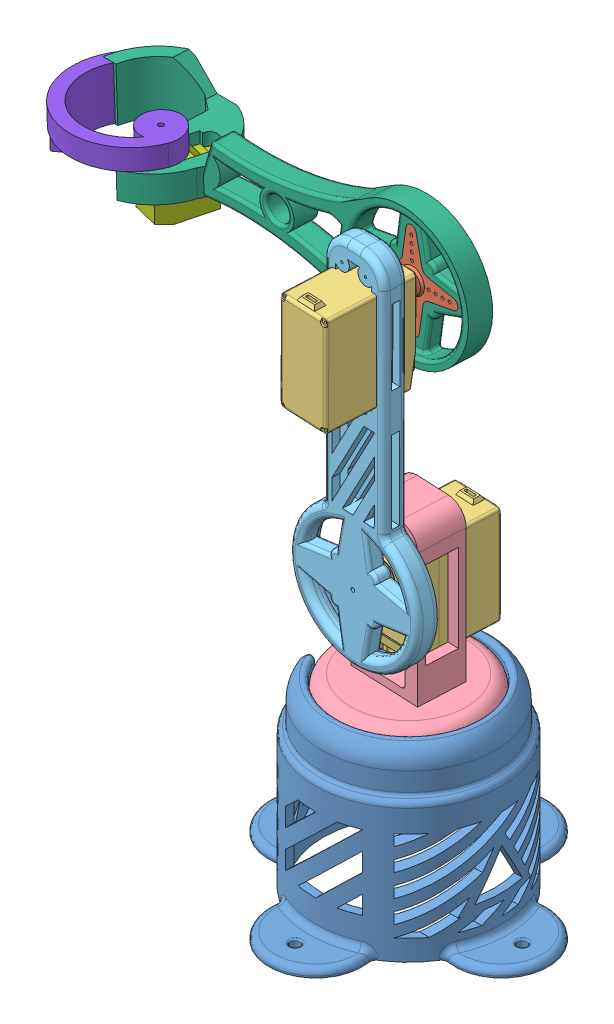
SolidWorks assembly Assem1, configuration Default. Lengths in mm.
Overall size (202.94 242.89 114.3).
12 component instances, 8 part files, 27 mates.
Components (placement in the parent):
- BASE-1: BASE [Default] at (34.7058 14.5894 97.2398) size (114.3 74.5 114.3)
- BigHorn-1: BigHorn [Default] at (44.9557 83.3474 97.2398) x (1 0 0) z (0 1 0) size (39 39 5.5)
- BigServo-1: BigServo [Default] at (25.5058 40.2074 97.2398) size (55 43.2 19.81)
- baseArm-1: baseArm [Default] at (35.4442 121.2694 87.7383) x (0.998997 0 0.044786) z (-0.044786 0 0.998997) size (57.66 73.66 57.66)
- BigServo-2: BigServo [Default] at (35.9471 120.992 69.6727) x (0 1 0) z (0.998997 0 0.044786) size (55 43.2 19.81)
- BigHorn-2: BigHorn [Default] at (44.2546 130.2432 113.2285) x (0.998984 0.004996 0.044785) z (-0.044786 0 0.998997) size (39 39 5.5)
- SecondArm-1: SecondArm [Default] at (32.9549 204.8069 119.0783) x (0.002786 0.999996 0.000125) z (-0.998993 0.002789 -0.044785) size (149.66 10.31 54.84)
- BigServo-3: BigServo [Default] at (33.1263 219.8634 139.081) x (0.002786 0.999996 0.000125) z (-0.998993 0.002789 -0.044785) size (55 43.2 19.81)
- BigHorn-3: BigHorn [Default] at (34.7066 239.3063 95.9685) x (-0.036819 0.999321 -0.001651) z (0.044786 0 -0.998997) size (39 39 5.5)
- GripArm-1: GripArm [Default] at (34.9418 229.0633 99.1573) x (-0.998318 -0.036856 -0.044755) z (0.036819 -0.999321 0.001651) size (164.52 47.62 54.84)
- S3114_servo_CAD_Model-1: S3114_servo_CAD_Model [Default] at (-64.0297 219.3331 99.3834) x (0.963437 0.035935 0.265513) z (-0.265392 -0.008186 0.964106) size (11 26.09 29)
- Gripper-1: Gripper [Default] at (-79.4937 227.162 95.1254) x (-0.962329 -0.035901 -0.269506) z (0.269382 0.008335 -0.962997) size (50.7 21.08 33.82)
Mates (geometry in assembly coordinates):
- Coincident1: coincident anti-aligned: plane of BigHorn-1 through (34.7058 83.4074 97.2398) normal (0 -1 0); plane of BigServo-1 through (25.5058 83.4074 97.2398) normal (0 1 0)
- Concentric1: concentric anti-aligned: circle of BigHorn-1; cylinder of BigServo-1 through (34.7058 78.4074 97.2398) axis (0 -1 0) radius 5.3
- Coincident3: coincident aligned: circle of BASE-1; circle of BigServo-1
- Concentric2: concentric aligned: circle of BASE-1; circle of BigServo-1
- Coincident4: coincident anti-aligned: plane of BASE-1 through (34.7058 78.7244 97.2398) normal (0 1 0); plane of baseArm-1 through (34.7058 78.7244 97.2398) normal (0 -1 0)
- Concentric3: concentric anti-aligned: circle of BASE-1; circle of baseArm-1
- Concentric5: concentric aligned: circle of BigServo-2; circle of baseArm-1
- Concentric7: concentric anti-aligned: cylinder of baseArm-1 through (30.1198 145.122 86.2284) axis (-0.044786 0 0.998997) radius 0.508; circle of BigServo-2
- Coincident7: coincident anti-aligned: plane of baseArm-1 through (39.8128 145.122 96.8731) normal (-0.044786 0 0.998997); plane of BigServo-2 through (42.1305 146.992 96.977) normal (0.044786 0 -0.998997)
- Concentric8: concentric anti-aligned: circle of BigServo-2; circle of BigHorn-2
- Coincident8: coincident anti-aligned: plane of BigServo-2 through (34.0124 120.992 112.8294) normal (-0.044786 0 0.998997); plane of BigHorn-2 through (34.0124 130.192 112.8294) normal (0.044786 0 -0.998997)
- Coincident11: coincident aligned: plane of BigHorn-2 through (44.2546 130.2432 113.2285) normal (0.044786 0 -0.998997); plane of SecondArm-1 through (34.0151 130.192 112.7694) normal (0.044786 0 -0.998997)
- Concentric9: concentric anti-aligned: circle of BigHorn-2; circle of SecondArm-1
- Coincident12: coincident anti-aligned: plane of BigHorn-2 through (39.6232 129.3585 113.0209) normal (0.981288 0.187452 0.043992); plane of SecondArm-1 through (39.6232 129.3585 113.0209) normal (-0.981288 -0.187452 -0.043992)
- Coincident13: coincident anti-aligned: plane of SecondArm-1 through (27.0154 245.8839 111.78) normal (0.044786 0 -0.998997); plane of BigServo-3 through (27.0154 245.8839 111.78) normal (-0.044786 0 0.998997)
- Concentric10: concentric anti-aligned: circle of SecondArm-1; circle of BigServo-3
- Concentric11: concentric anti-aligned: circle of SecondArm-1; circle of BigServo-3
- Coincident14: coincident anti-aligned: plane of BigServo-3 through (35.061 219.8634 95.9244) normal (0.044786 0 -0.998997); plane of BigHorn-3 through (35.0866 229.0633 95.9255) normal (-0.044786 0 0.998997)
- Concentric12: concentric anti-aligned: circle of BigServo-3; circle of BigHorn-3
- Coincident15: coincident anti-aligned: plane of BigHorn-3 through (34.7849 239.3063 94.2203) normal (0.044786 0 -0.998997); plane of GripArm-1 through (42.5839 222.1628 94.5699) normal (-0.044786 0 0.998997)
- Concentric13: concentric aligned: circle of BigHorn-3; circle of GripArm-1
- Coincident16: coincident anti-aligned: plane of BigHorn-3 through (41.8507 238.2496 96.2888) normal (0.988265 -0.146181 0.044304); plane of GripArm-1 through (40.5101 230.1311 99.4069) normal (-0.988265 0.146181 -0.044304)
- Coincident17: coincident anti-aligned: plane of GripArm-1 through (-66.7447 219.2431 105.481) normal (-0.036819 0.999321 -0.001651); plane of S3114_servo_CAD_Model-1 through (-64.0297 219.3331 99.3834) normal (0.036819 -0.999321 0.001651)
- Concentric14: concentric aligned: circle of GripArm-1; circle of S3114_servo_CAD_Model-1
- Concentric15: concentric aligned: circle of GripArm-1; circle of S3114_servo_CAD_Model-1
- Concentric17: concentric anti-aligned: circle of S3114_servo_CAD_Model-1; circle of Gripper-1
- Coincident19: coincident anti-aligned: plane of S3114_servo_CAD_Model-1 through (-64.339 227.7274 99.3695) normal (-0.036819 0.999321 -0.001651); plane of Gripper-1 through (-79.4937 227.162 95.1254) normal (0.036819 -0.999321 0.001651)
